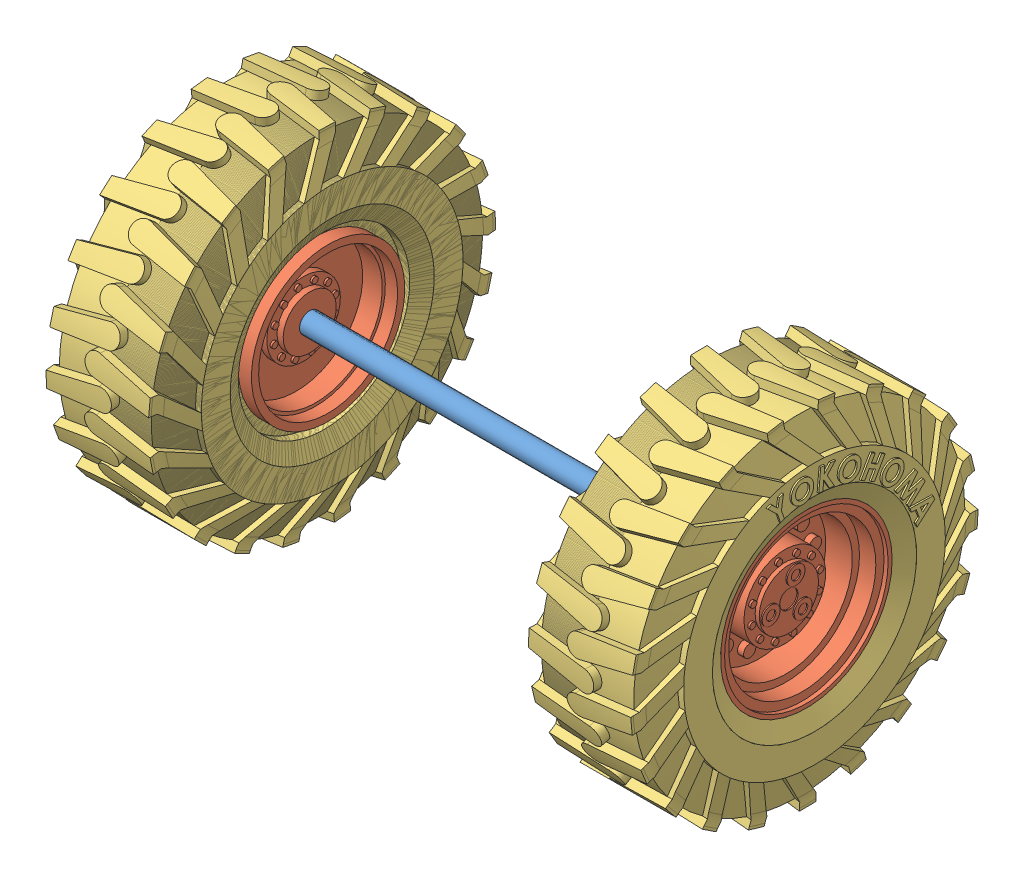
SolidWorks assembly 5.SubAssembly_WheelAndAxle, configuration Default. Lengths in mm.
Overall size (372 286.79 286.55).
5 component instances, 3 part files, 4 mates.
Components (placement in the parent):
- SubPart 5-Axle Rod-1: SubPart 5-Axle Rod [Default] at (109.0885 135.572 242.7612) size (297.5 12.5 12.5)
- SubPart 5-Rim-1: SubPart 5-Rim [Default] at (255.6235 135.572 242.7612) x (1 0 0) z (0 0.308568 0.951202) size (67.5 105 105)
- SubPart 5-Wheel-3: SubPart 5-Wheel [Default] at (256.5885 135.572 242.7612) x (1 0 0) z (0 0.439468 0.898258) size (76 214.56 214.04)
- SubPart 5-Wheel-4: SubPart 5-Wheel [Default] at (-38.4115 135.6011 242.8207) x (-1 0 0) z (0 -0.439468 -0.898258) size (76 214.56 214.04)
- SubPart 5-Rim-2: SubPart 5-Rim [Default] at (-37.4465 135.572 242.7612) x (-1 0 0) z (0 -0.308568 -0.951202) size (67.5 105 105)
Mates (geometry in assembly coordinates):
- Concentric1: concentric anti-aligned: circle of SubPart 5-Axle Rod-1; circle of SubPart 5-Rim-1
- Coincident2: coincident anti-aligned: plane of SubPart 5-Axle Rod-1 through (257.8385 135.572 242.7612) normal (1 0 0); plane of SubPart 5-Rim-1 through (257.8385 135.572 242.7612) normal (-1 0 0)
- Concentric2: concentric aligned: circle of SubPart 5-Rim-1; circle of SubPart 5-Wheel-3
- Coincident4: coincident anti-aligned: plane of SubPart 5-Rim-1 through (283.5885 180.1834 228.2894) normal (-1 0 0); plane of SubPart 5-Wheel-3 through (283.5885 135.572 242.7612) normal (1 0 0)
